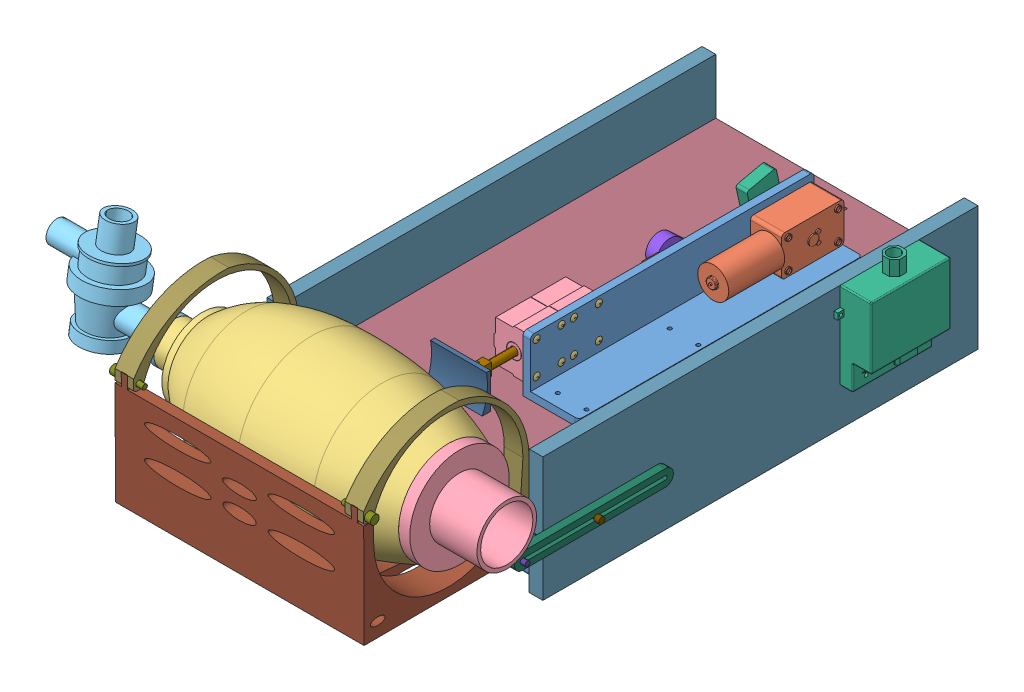
SolidWorks assembly Ventilator assembly, configuration Default. Lengths in mm.
Overall size (608.77 327.42 499.47).
47 component instances, 25 part files, 63 mates.
Components (placement in the parent):
- Base_part-1: Base_part [Default] at (-52.7018 113.3047 82.1767) size (45 45 228)
- DC_motor-1: DC_motor [Default] at (-51.7018 113.3047 82.1767) size (27.5 32 98)
- screws-1: screws [Default] at (107.2366 329.8825 235.4772) x (-1 0 0) z (0 -0.924225 -0.381849) size (10.88 5.61 5.61)
- screws-2: screws [Default] at (107.2366 329.8825 195.4772) x (-1 0 0) z (0 -0.924225 -0.381849) size (10.88 5.61 5.61)
- screws-3: screws [Default] at (107.2366 306.8825 235.4772) x (-1 0 0) z (0 -0.924225 -0.381849) size (10.88 5.61 5.61)
- screws-4: screws [Default] at (107.2366 306.8825 195.4772) x (-1 0 0) z (0 -0.924225 -0.381849) size (10.88 5.61 5.61)
- Rod way-1: Rod way [Default] at (-52.7018 113.3047 82.1767) size (25 35 56.3)
- screws-5: screws [Default] at (-52.7018 113.3047 32.1767) size (10.88 5.61 5.61)
- screws-6: screws [Default] at (-52.7018 73.5611 33.9508) x (1 0 0) z (0 0.061818 0.998087) size (10.88 5.61 5.61)
- screws-7: screws [Default] at (-52.7018 0.7067 79.0795) x (1 0 0) z (0 0.396338 0.918105) size (10.88 5.61 5.61)
- screws-8: screws [Default] at (-52.7018 200.4914 90.8666) x (1 0 0) z (0 -0.383497 0.923542) size (10.88 5.61 5.61)
- screws-9: screws [Default] at (-52.7018 113.3047 52.1767) size (10.88 5.61 5.61)
- screws-10: screws [Default] at (-52.7018 113.3047 62.1767) size (10.88 5.61 5.61)
- screws-11: screws [Default] at (-52.7018 87.3047 62.1767) size (10.88 5.61 5.61)
- screws-12: screws [Default] at (-52.7018 87.3047 82.1767) size (10.88 5.61 5.61)
- Brown_small_rod-1: Brown_small_rod [Default] at (19.2674 102.3159 87.7533) x (0 0.807102 0.590412) z (1 0 0) size (7.5 7.5 18)
- Back_rotat_part-1: Back_rotat_part [Default] at (-53.7018 91.6899 111.2833) x (1 0 0) z (0 0.976594 0.21509) size (9 23.97 68.75)
- second_rod-1: second_rod [Default] at (-53.7018 84.4623 111.2264) x (1 0 0) z (0 0.538464 0.842648) size (23 9.99 10.22)
- mid_rotat_part-1: mid_rotat_part [Default] at (-53.7018 83.1521 110.5462) x (1 0 0) z (0 0.400572 0.916265) size (11.98 22.02 103.99)
- second_rod-2: second_rod [Default] at (-53.7018 126.1289 169.8641) x (1 0 0) z (0 -0.400569 -0.916266) size (23 9.99 10.22)
- Last_translation-1: Last_translation [Default] at (3.4962 122.0308 201.9504) x (-0.91495 -0.403568 0) z (-0.403568 0.91495 0) size (12.55 175 16.77)
- soft pad-1: soft pad [Default] at (-52.7018 113.3047 78.9691) size (45 28.6 20.49)
- Base assembly-2: Base assembly [Default] at (135.8935 265.0846 411.8174) x (0 -0.003915 0.999992) z (0 -0.999992 -0.003915) size (483.09 242 163.86)
  - bag_support-1: bag_support [Default] at (69.2658 27.6261 217.7217) size (132.92 200 93.26)
  - Part6-1: Part6 [Default] at (69.2658 227.6261 217.7217) x (1 0 0) z (0 1 0) size (132.92 114.72 15)
  - bottom base-1: bottom base [Default] at (-229.5822 133.6044 170.88) x (0.999992 0 -0.003915) z (0 -1 0) size (350 11 200)
  - side support-1: side support [Default] at (-237.5882 27.6591 167.1447) x (0.999992 0 -0.003915) z (0 -1 0) size (350 100 11)
  - side support-2: side support [Default] at (-237.5882 238.5931 167.1447) x (0.999992 0 -0.003915) z (0 -1 0) size (350 100 11)
  - Part7-4: Part7 [Default] at (69.2658 227.6261 200.1018) x (1 0 0) z (0 1 0) size (127.81 13 17)
  - Part7-5: Part7 [Default] at (69.2658 27.6261 167.5182) x (1 0 0) z (0 -1 0) size (127.81 13 17)
  - Part6-4: Part6 [Default] at (69.2658 42.6261 217.7217) x (1 0 0) z (0 1 0) size (132.92 114.72 15)
  - Part8-5: Part8 [Default] at (-10.2651 47.6261 -226.7075) x (1 0 0) z (0 -1 0) size (7 7 25)
  - Part8-6: Part8 [Default] at (224.1601 207.6261 -226.7075) x (-1 0 0) z (0 1 0) size (7 7 25)
  - Part8-7: Part8 [Default] at (-135.0725 207.6261 508.5734) x (1 0 0) z (0 1 0) size (7 7 25)
  - Part8-8: Part8 [Default] at (99.3527 47.6261 508.5734) x (-1 0 0) z (0 -1 0) size (7 7 25)
  - added_pin-1: added_pin [Default] at (0.3999 214.6261 183.81) size (4 34 4)
  - added_pin-2: added_pin [Default] at (0.3999 40.6261 183.81) x (1 0 0) z (0 0 -1) size (4 34 4)
  - other_pin-1: other_pin [Default] at origin size (5 17.03 5)
  - other_pin-2: other_pin [Default] at (0 255.2522 367.62) x (1 0 0) z (0 0 -1) size (5 17.03 5)
- MURI_ASSEMBLY-1: MURI_ASSEMBLY [Default] at (108.2344 34.1047 157.1767) x (-1 0 0) z (0 0 -1) size (115 50 215)
  - MURI_project1-2: MURI_project1 [Default] at origin size (115 50 215)
  - muri_PROJECT2-9: muri_PROJECT2 [Default] at (2 20 -18) size (111 30 195)
- bag_revised-1: bag_revised [Default] at (-111.7212 87.411 489.465) x (1 0 0) z (0 0.586706 0.8098) size (219.99 120.3 120.3)
- cover_revised-1: cover_revised [Default] at (108.2674 179.8459 484.1892) x (1 0 0) z (0 0.563802 -0.82591) size (289.79 307.42 80)
- top_revised-2: top_revised [Default] at (-18.4202 76.8032 464.0285) x (-1 0 0) z (0 -0.162809 -0.986658) size (98.99 86.04 48.99)
- Controller-1: Controller [Default] at (119.2344 69.6047 85.9806) x (0 0 1) z (0 -1 0) size (74 25 82)
- Bolt-1: Bolt [Default] at (-52.7018 113.3047 78.9691) size (12 7.25 6.84)
Mates (geometry in assembly coordinates):
- Distance2: distance = 2 mm anti-aligned: plane of DC_motor-1 through (32.2674 113.3047 82.1767) normal (-1 0 0); plane of Base_part-1 through (30.2674 140.1047 310.1767) normal (1 0 0)
- Concentric1: concentric aligned: cylinder of Base_part-1 through (69.2674 120.6047 110.1767) axis (-1 0 0) radius 4; cylinder of DC_motor-1 through (58.2674 120.6047 110.1767) axis (-1 0 0) radius 4
- Parallel1: parallel aligned: plane of Base_part-1 through (24.2674 140.1047 310.1767) normal (0 1 0); plane of DC_motor-1 through (57.2674 136.6047 135.1767) normal (0 1 0)
- Coincident4: coincident anti-aligned: plane of Base_part-1 through (24.2674 101.1047 310.1767) normal (-1 0 0); plane of screws-1 through (24.2674 123.7804 150.3248) normal (1 0 0)
- Concentric2: concentric aligned: cylinder of Base_part-1 through (69.2674 132.1047 130.1767) axis (-1 0 0) radius 2; cylinder of screws-1 through (34.2674 132.1047 130.1767) axis (-1 0 0) radius 1.875
- Coincident5: coincident anti-aligned: plane of Base_part-1 through (24.2674 101.1047 310.1767) normal (-1 0 0); plane of screws-2 through (24.2674 123.7804 110.3248) normal (1 0 0)
- Concentric3: concentric aligned: cylinder of Base_part-1 through (69.2674 132.1047 90.1767) axis (-1 0 0) radius 2; cylinder of screws-2 through (34.2674 132.1047 90.1767) axis (-1 0 0) radius 1.875
- Coincident6: coincident anti-aligned: plane of Base_part-1 through (24.2674 101.1047 310.1767) normal (-1 0 0); plane of screws-3 through (24.2674 100.7804 150.3248) normal (1 0 0)
- Concentric4: concentric aligned: cylinder of Base_part-1 through (69.2674 109.1047 130.1767) axis (-1 0 0) radius 2; cylinder of screws-3 through (34.2674 109.1047 130.1767) axis (-1 0 0) radius 1.875
- Coincident7: coincident anti-aligned: plane of Base_part-1 through (24.2674 101.1047 310.1767) normal (-1 0 0); plane of screws-4 through (24.2674 100.7804 110.3248) normal (1 0 0)
- Concentric5: concentric aligned: cylinder of Base_part-1 through (69.2674 109.1047 90.1767) axis (-1 0 0) radius 2; cylinder of screws-4 through (34.2674 109.1047 90.1767) axis (-1 0 0) radius 1.875
- Coincident8: coincident anti-aligned: plane of Base_part-1 through (24.2674 101.1047 310.1767) normal (-1 0 0); plane of Rod way-1 through (24.2674 113.3047 82.1767) normal (1 0 0)
- Concentric6: concentric anti-aligned: cylinder of Base_part-1 through (69.2674 135.1047 305.1767) axis (-1 0 0) radius 2; cylinder of Rod way-1 through (14.2674 135.1047 305.1767) axis (1 0 0) radius 2
- Concentric7: concentric anti-aligned: cylinder of Base_part-1 through (69.2674 135.1047 255.1767) axis (-1 0 0) radius 2; cylinder of Rod way-1 through (14.2674 135.1047 255.1767) axis (1 0 0) radius 2
- Concentric8: concentric anti-aligned: cylinder of Base_part-1 through (69.2674 135.1047 255.1767) axis (-1 0 0) radius 2; cylinder of screws-5 through (20.2674 135.1047 255.1767) axis (1 0 0) radius 1.875
- Coincident9: coincident anti-aligned: plane of Base_part-1 through (30.2674 140.1047 310.1767) normal (1 0 0); plane of screws-5 through (30.2674 113.3047 255.1767) normal (-1 0 0)
- Coincident10: coincident anti-aligned: plane of Base_part-1 through (30.2674 140.1047 310.1767) normal (1 0 0); plane of screws-6 through (30.2674 87.3464 256.5243) normal (-1 0 0)
- Concentric9: concentric anti-aligned: cylinder of Base_part-1 through (69.2674 109.1047 255.1767) axis (-1 0 0) radius 2; cylinder of screws-6 through (20.2674 109.1047 255.1767) axis (1 0 0) radius 1.875
- Coincident11: coincident anti-aligned: plane of Base_part-1 through (30.2674 140.1047 310.1767) normal (1 0 0); plane of screws-7 through (30.2674 89.09 283.8169) normal (-1 0 0)
- Concentric10: concentric anti-aligned: cylinder of Base_part-1 through (69.2674 109.1047 275.1767) axis (-1 0 0) radius 2; cylinder of screws-7 through (20.2674 109.1047 275.1767) axis (1 0 0) radius 1.875
- Coincident12: coincident anti-aligned: plane of Base_part-1 through (30.2674 140.1047 310.1767) normal (1 0 0); plane of screws-8 through (30.2674 114.9715 296.8165) normal (-1 0 0)
- Concentric11: concentric anti-aligned: cylinder of Base_part-1 through (69.2674 135.1047 305.1767) axis (-1 0 0) radius 2; cylinder of screws-8 through (20.2674 135.1047 305.1767) axis (1 0 0) radius 1.875
- Coincident13: coincident anti-aligned: plane of Base_part-1 through (30.2674 140.1047 310.1767) normal (1 0 0); plane of screws-9 through (30.2674 113.3047 275.1767) normal (-1 0 0)
- Concentric12: concentric anti-aligned: cylinder of Base_part-1 through (69.2674 135.1047 275.1767) axis (-1 0 0) radius 2; cylinder of screws-9 through (20.2674 135.1047 275.1767) axis (1 0 0) radius 1.875
- Coincident14: coincident anti-aligned: plane of Base_part-1 through (30.2674 140.1047 310.1767) normal (1 0 0); plane of screws-10 through (30.2674 113.3047 285.1767) normal (-1 0 0)
- Concentric13: concentric anti-aligned: cylinder of Base_part-1 through (69.2674 135.1047 285.1767) axis (-1 0 0) radius 2; cylinder of screws-10 through (20.2674 135.1047 285.1767) axis (1 0 0) radius 1.875
- Coincident15: coincident anti-aligned: plane of Base_part-1 through (30.2674 140.1047 310.1767) normal (1 0 0); plane of screws-11 through (30.2674 87.3047 285.1767) normal (-1 0 0)
- Concentric14: concentric anti-aligned: cylinder of Base_part-1 through (69.2674 109.1047 285.1767) axis (-1 0 0) radius 2; cylinder of screws-11 through (20.2674 109.1047 285.1767) axis (1 0 0) radius 1.875
- Coincident16: coincident anti-aligned: plane of Base_part-1 through (30.2674 140.1047 310.1767) normal (1 0 0); plane of screws-12 through (30.2674 87.3047 305.1767) normal (-1 0 0)
- Concentric15: concentric anti-aligned: cylinder of Base_part-1 through (69.2674 109.1047 305.1767) axis (-1 0 0) radius 2; cylinder of screws-12 through (20.2674 109.1047 305.1767) axis (1 0 0) radius 1.875
- Coincident17: coincident aligned: plane of Base_part-1 through (30.2674 140.1047 310.1767) normal (1 0 0); plane of Brown_small_rod-1 through (30.2674 120.6047 110.1767) normal (1 0 0)
- Concentric16: concentric anti-aligned: cylinder of Base_part-1 through (69.2674 120.6047 110.1767) axis (-1 0 0) radius 4; cylinder of Brown_small_rod-1 through (1.6608 120.6047 110.1767) axis (1 0 0) radius 3.75
- Coincident19: coincident aligned: plane of Brown_small_rod-1 through (12.2674 102.3159 87.7533) normal (-1 0 0); plane of Back_rotat_part-1 through (12.2674 91.6899 111.2833) normal (-1 0 0)
- Concentric18: concentric anti-aligned: cylinder of Brown_small_rod-1 through (1.6608 120.6047 110.1767) axis (1 0 0) radius 3.75; cylinder of Back_rotat_part-1 through (21.2674 120.6047 110.1767) axis (-1 0 0) radius 4
- Coincident21: coincident aligned: plane of Back_rotat_part-1 through (21.2674 91.6899 111.2833) normal (1 0 0); plane of second_rod-1 through (21.2674 88.1449 102.5303) normal (1 0 0)
- Concentric19: concentric aligned: cylinder of Back_rotat_part-1 through (21.2684 88.1449 102.5303) axis (-1 0 0) radius 4; cylinder of second_rod-1 through (21.2674 88.1449 102.5303) axis (-1 0 0) radius 3.75
- Parallel3: parallel aligned: plane of Back_rotat_part-1 through (12.2674 149.3556 103.7388) normal (0 0.21509 -0.976594); plane of second_rod-1 through (1.2674 89.1931 97.4102) normal (0 0.21509 -0.976594)
- Concentric20: concentric anti-aligned: cylinder of second_rod-1 through (21.2674 88.1449 102.5303) axis (-1 0 0) radius 3.75; cylinder of mid_rotat_part-1 through (1.2674 88.1449 102.5303) axis (1 0 0) radius 4
- Coincident23: coincident anti-aligned: plane of second_rod-1 through (1.2674 84.4623 111.2264) normal (1 0 0); plane of mid_rotat_part-1 through (1.2674 88.1449 102.5303) normal (-1 0 0)
- Concentric21: concentric aligned: cylinder of mid_rotat_part-1 through (10.2674 121.1362 177.88) axis (-1 0 0) radius 4; cylinder of second_rod-2 through (21.2674 121.1362 177.88) axis (-1 0 0) radius 3.75
- Coincident25: coincident anti-aligned: plane of mid_rotat_part-1 through (1.2674 88.1449 102.5303) normal (-1 0 0); plane of second_rod-2 through (1.2674 126.1289 169.8641) normal (1 0 0)
- Parallel5: parallel anti-aligned: plane of mid_rotat_part-1 through (-53.7018 103.6551 157.445) normal (0 0.400569 0.916266); plane of second_rod-2 through (1.2674 121.1817 172.2857) normal (0 -0.400569 -0.916266)
- Concentric24: concentric anti-aligned: cylinder of Rod way-1 through (15.2674 120.8547 235.8133) axis (0 0 1) radius 3.25; cylinder of Last_translation-1 through (15.2674 120.8547 329.9504) axis (0 0 -1) radius 3
- Parallel7: parallel anti-aligned: plane of mid_rotat_part-1 through (10.2674 88.1449 102.5303) normal (1 0 0); plane of Last_translation-1 through (13.3316 110.65 169.9504) normal (-1 0 0)
- Concentric25: concentric aligned: cylinder of second_rod-2 through (21.2674 121.1362 177.88) axis (-1 0 0) radius 3.75; cylinder of Last_translation-1 through (18.7674 121.1362 177.88) axis (-1 0 0) radius 4
- Coincident29: coincident anti-aligned: plane of Last_translation-1 through (14.1964 125.8547 334.9504) normal (-1 0 0); plane of soft pad-1 through (14.1964 113.3047 78.9691) normal (1 0 0)
- Concentric26: concentric aligned: cylinder of Last_translation-1 through (24.1964 120.8547 339.8307) axis (-1 0 0) radius 2.5; cylinder of soft pad-1 through (14.3064 120.8547 339.8307) axis (-1 0 0) radius 2.5
- Coincident30: coincident anti-aligned: plane of Last_translation-1 through (3.4962 122.0308 334.9504) normal (0 0 1); plane of soft pad-1 through (11.7664 125.8547 334.9504) normal (0 0 -1)
- Coincident32: coincident anti-aligned: plane of Base_part-1 through (30.2674 95.1047 310.1767) normal (0 -1 0); plane of Base assembly-2/bottom base-1 through (2.2892 95.1047 181.568) normal (0 1 0)
- Distance4: distance = 43 mm aligned: plane of Base_part-1 through (-52.7018 113.3047 82.1767) normal (0 0 -1); plane of Base assembly-2/bottom base-1 through (-91.7326 84.1047 39.1767) normal (0 0 -1)
- Coincident34: coincident aligned: plane of Base_part-1 through (24.2674 101.1047 310.1767) normal (-1 0 0); plane of Base assembly-2/bottom base-1 through (24.2674 95.1047 69.1767) normal (-1 0 0)
- Coincident35: coincident anti-aligned: plane of Base assembly-2/bottom base-1 through (2.2892 84.1047 181.568) normal (0 -1 0); plane of MURI_ASSEMBLY-1/muri_PROJECT2-9 through (106.2344 84.1047 175.1767) normal (0 1 0)
- Coincident37: coincident anti-aligned: plane of MURI_ASSEMBLY-1/MURI_project1-2 through (108.2344 84.1047 372.1767) normal (1 0 0); plane of Base assembly-2/side support-1 through (108.2344 98.8714 173.5767) normal (-1 0 0)
- Concentric27: concentric aligned: circle of Base assembly-2; circle of bag_revised-1
- Coincident38: coincident aligned: plane of Base assembly-2/bag_support-1 through (108.2674 353.8291 458.3521) normal (1 0 0); plane of bag_revised-1 through (108.2674 165.2066 433.1015) normal (1 0 0)
- Concentric28: concentric aligned: circle of bag_revised-1; circle of cover_revised-1
- Coincident41: coincident anti-aligned: plane of bag_revised-1 through (108.2674 165.2066 433.1015) normal (1 0 0); plane of cover_revised-1 through (108.2674 102.9664 431.7079) normal (-1 0 0)
- Concentric30: concentric anti-aligned: circle of bag_revised-1; circle of top_revised-2
- Coincident43: coincident anti-aligned: plane of bag_revised-1 through (-111.7212 149.7599 444.2927) normal (-1 0 0); plane of top_revised-2 through (-111.7212 152.7768 451.492) normal (1 0 0)
- Coincident44: coincident anti-aligned: plane of Base assembly-2/side support-1 through (119.2344 98.8714 173.5767) normal (1 0 0); plane of Controller-1 through (119.2344 69.6047 85.9806) normal (-1 0 0)
- Coincident45: coincident aligned: plane of Base assembly-2/side support-1 through (119.2344 139.6047 39.1767) normal (0 1 0); plane of Controller-1 through (129.2344 139.6047 85.9806) normal (0 1 0)
- Concentric31: concentric anti-aligned: circle of Last_translation-1; circle of Bolt-1
- Coincident46: coincident anti-aligned: plane of Last_translation-1 through (18.7674 115.8547 344.9504) normal (1 0 0); plane of Bolt-1 through (18.7674 113.3047 78.9691) normal (-1 0 0)
